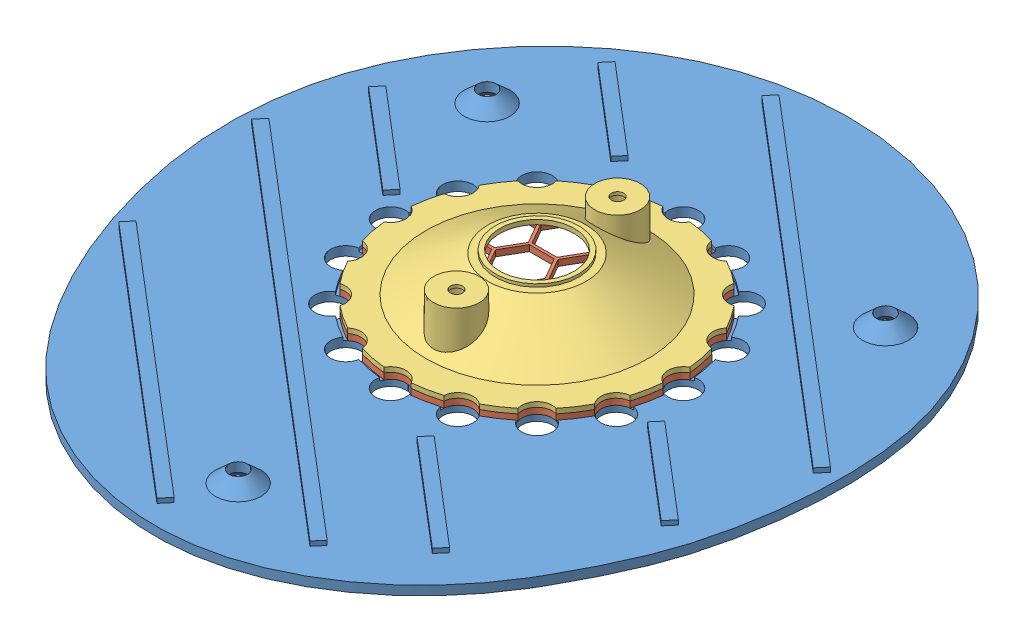
SolidWorks assembly BracketAssembly, configuration Default. Lengths in mm.
Overall size (103.39 10.16 123.19).
3 component instances, 3 part files, 7 mates.
Components (placement in the parent):
- led heatsink mount - base-1: led heatsink mount - base [Default] at (-33.0463 -3.6175 11.2537) size (103.39 3.55 123.19)
- Diffuser-1: Diffuser [Default] at (-33.0463 -2.6175 11.2537) x (0 0 1) z (-1 0 0) size (45.7 1 45.7)
- led heatsink mount-2: led heatsink mount [Default] at (-33.0463 -3.2075 11.2537) x (-0.586905 0 0.809656) z (-0.809656 0 -0.586905) size (45.91 8.11 45.91)
Mates (geometry in assembly coordinates):
- Coincident5: coincident anti-aligned: plane of Diffuser-1 through (-33.0463 -1.6175 11.2537) normal (0 1 0); plane of led heatsink mount-2 through (21.097 -1.6175 10.1257) normal (0 -1 0)
- Coincident6: coincident anti-aligned: plane of led heatsink mount - base-1 through (-33.0463 -2.6175 11.2537) normal (0 1 0); plane of Diffuser-1 through (-33.0463 -2.6175 11.2537) normal (0 -1 0)
- Coincident7: coincident anti-aligned: plane of led heatsink mount - base-1 through (-33.0463 -2.6175 11.2537) normal (0 1 0); plane of Diffuser-1 through (-33.0463 -2.6175 11.2537) normal (0 -1 0)
- Concentric15: concentric aligned: cylinder of led heatsink mount - base-1 through (-16.0758 -2.1175 28.2243) axis (0 -1 0) radius 2.5; cylinder of Diffuser-1 through (-16.0758 -1.6175 28.2243) axis (0 -1 0) radius 2.5
- Concentric16: concentric aligned: cylinder of led heatsink mount - base-1 through (-33.0463 -2.1175 35.2537) axis (0 -1 0) radius 2.5; cylinder of Diffuser-1 through (-33.0463 -1.6175 35.2537) axis (0 -1 0) radius 2.5
- Concentric18: concentric aligned: cylinder of Diffuser-1 through (-33.0463 -1.6175 35.2537) axis (0 -1 0) radius 2.5; cylinder of led heatsink mount-2 through (-33.0463 26.7925 35.2537) axis (0 -1 0) radius 2.5
- Concentric19: concentric aligned: cylinder of Diffuser-1 through (-16.0758 -1.6175 28.2243) axis (0 -1 0) radius 2.5; cylinder of led heatsink mount-2 through (-16.0758 26.7925 28.2243) axis (0 -1 0) radius 2.5
